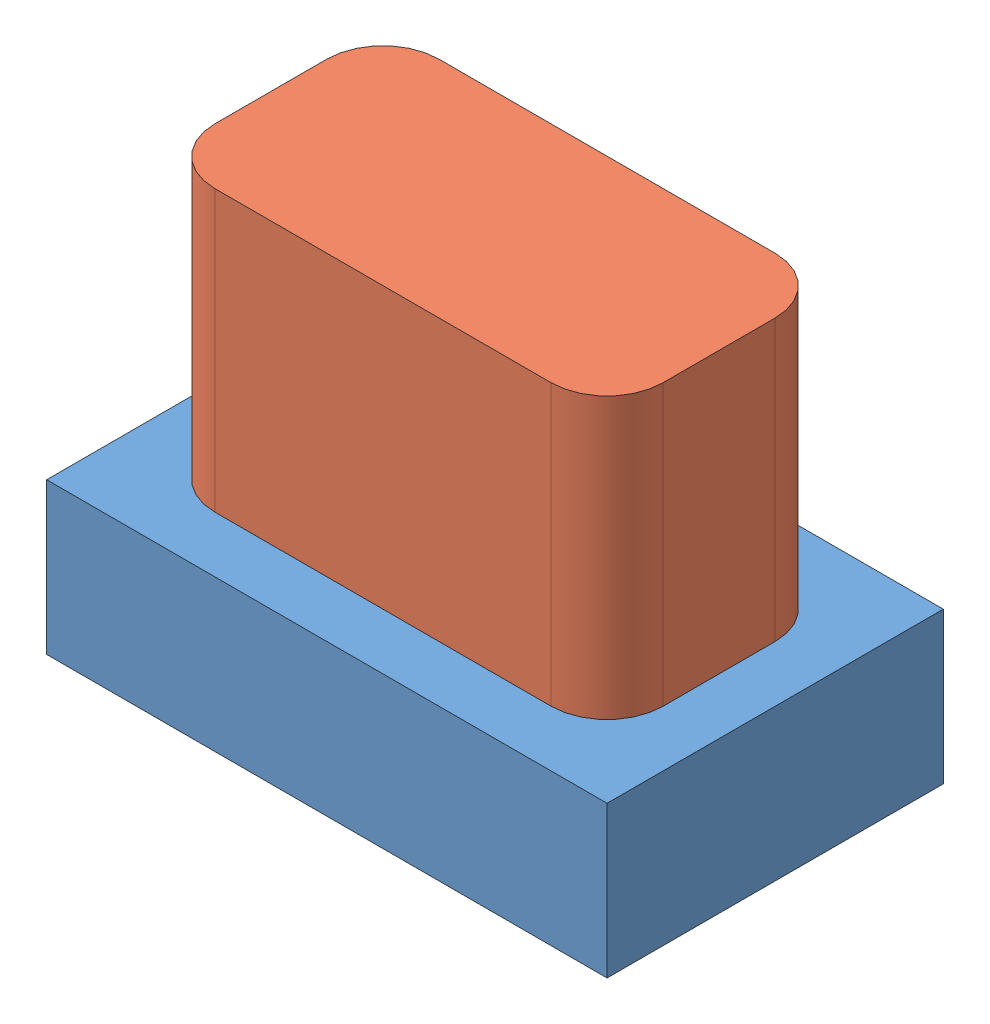
SolidWorks assembly Assem1, configuration Default. Lengths in mm.
Overall size (10 7.7 6).
2 component instances, 2 part files, 4 mates.
Components (placement in the parent):
- button1_base-1: button1_base [Default] at (3.726 3.1317 8.18) size (10 2.7 6)
- button1-1: button1 [Default] at (3.726 5.8317 8.18) size (8 5 4)
Mates (geometry in assembly coordinates):
- Coincident1: coincident: plane of button1_base-1 through (3.726 5.8317 8.18) normal (0 1 0); plane of button1-1 through (0.726 5.8317 7.18) normal (0 -1 0)
- Distance1: distance = 1 mm: line of button1_base-1 through (-1.274 5.8317 11.18) axis (1 0 0); line of button1-1 through (0.726 5.8317 10.18) axis (1 0 0)
- Distance2: distance = 1 mm: line of button1-1 through (-0.274 5.8317 7.18) axis (0 0 1); line of button1_base-1 through (-1.274 5.8317 5.18) axis (0 0 1)
- Distance3: distance = 1 mm: line of button1_base-1 through (8.726 5.8317 11.18) axis (0 0 -1); moEndPointRef_w of button1-1
